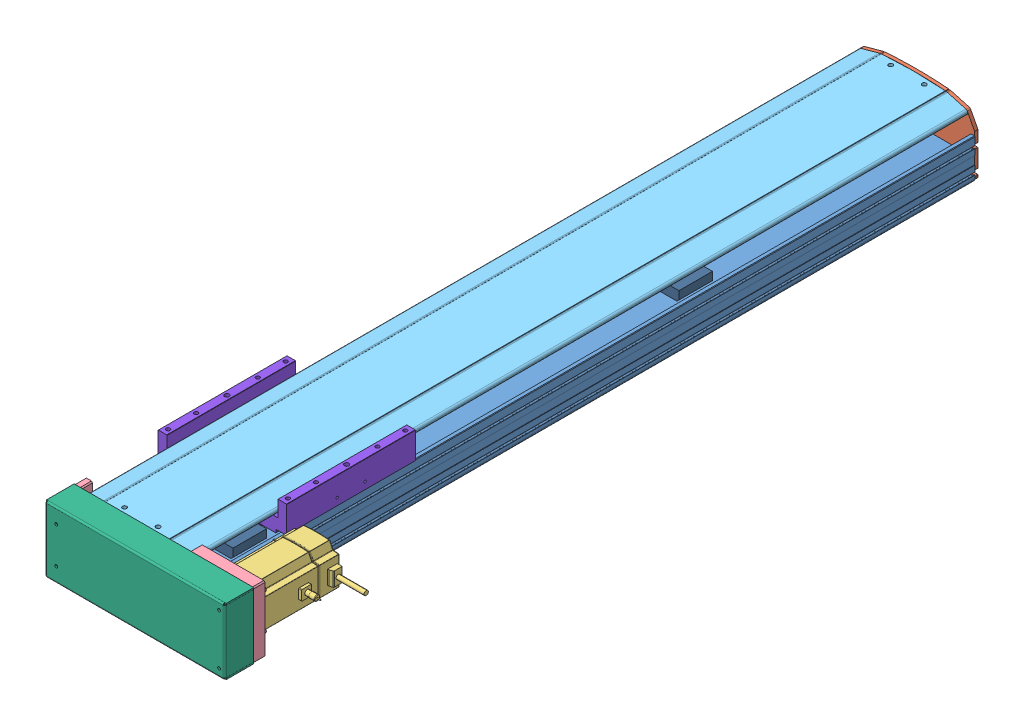
SolidWorks assembly S22M-BL-750W, configuration 默认. Lengths in mm.
Overall size (384.9 122 1448.01).
13 component instances, 10 part files, 39 mates.
Components (placement in the parent):
- S22-BL底座^S22M-BL-750W-1: S22-BL底座^S22M-BL-750W [默认] at origin size (220 71.7 1370) (virtual)
- S22-GY侧盖^S22M-BL-750W-1: S22-GY侧盖^S22M-BL-750W [默认] at (0 0 -691) size (219 117 6) (virtual)
- 750W电机^S22M-BL-750W-1: 750W电机^S22M-BL-750W [默认] at (162.7 60.3 543) x (0 1 0) z (0 0 1) size (82 139.7 182) (virtual)
- S22-BL-P75电机板^S22M-BL-750W-1: S22-BL-P75电机板^S22M-BL-750W [默认] at (0 -0.2 685) size (321 118 20) (virtual)
- S22-BL上盖^S22M-BL-750W-1: S22-BL上盖^S22M-BL-750W [默认] at (0 117.9988 10) size (193.4 19.6 1390) (virtual)
- S22-BL盖子^S22M-BL-750W-1: S22-BL盖子^S22M-BL-750W [默认] at (50.5 59.8 757) size (321.02 118 52.01) (virtual)
- EE-SX672 传感器^S22M-BL-750W-1: EE-SX672 传感器^S22M-BL-750W [默认] at (-116.75 60.4 -424.15) x (-1 0 0) z (0 0 1) size (13.5 27.4 26.1) (virtual)
- EE-SX672 传感器^S22M-BL-750W-2: EE-SX672 传感器^S22M-BL-750W [默认] at (-116.75 60.4 444.9) x (-1 0 0) z (0 0 1) size (13.5 27.4 26.1) (virtual)
- EE-SX672 传感器^S22M-BL-750W-3: EE-SX672 传感器^S22M-BL-750W [默认] at (-116.75 60.4 418.8) x (-1 0 0) z (0 0 1) size (13.5 27.4 26.1) (virtual)
- S22-BL-SFS25滑座^S22M-BL-750W-1: S22-BL-SFS25滑座^S22M-BL-750W [默认] at (0 0.3 435) size (230 80 230) (virtual)
- 复件 外置感应片ST22^S22M-BL-750W-1: 复件 外置感应片ST22^S22M-BL-750W [Default] at (-115 64.3 435) x (0 0 -1) z (1 0 0) size (70 28 1) (virtual)
- 滑座S22M^S22M-BL-750W-1: 滑座S22M^S22M-BL-750W [Default] at (0 60.3 570) size (198 57 60) (virtual)
- 滑座S22M^S22M-BL-750W-2: 滑座S22M^S22M-BL-750W [Default] at (0 60.3 -227) size (198 57 60) (virtual)
Mates (geometry in assembly coordinates):
- 重合1: coincident: plane of S22-BL底座^S22M-BL-750W-1 through (0 0 0) normal (1 0 0); plane of assembly through (0 0 0) normal (1 0 0)
- 重合2: coincident: plane of S22-BL底座^S22M-BL-750W-1 through (0 0 0) normal (0 1 0); plane of assembly through (0 0 0) normal (0 1 0)
- 重合3: coincident: plane of S22-BL底座^S22M-BL-750W-1 through (0 0 0) normal (0 0 1); plane of assembly through (0 0 0) normal (0 0 1)
- 重合4: coincident: plane of S22-BL底座^S22M-BL-750W-1 through (-104.5 14 -685) normal (0 0 -1); plane of S22-GY侧盖^S22M-BL-750W-1 through (0 -619.785 -685) normal (0 0 1)
- 重合5: coincident: plane of S22-BL底座^S22M-BL-750W-1 through (0 0 0) normal (1 0 0); plane of S22-GY侧盖^S22M-BL-750W-1 through (0 0 -691) normal (1 0 0)
- 重合6: coincident: plane of S22-BL底座^S22M-BL-750W-1 through (0 0 0) normal (0 1 0); plane of S22-GY侧盖^S22M-BL-750W-1 through (0 0 -691) normal (0 1 0)
- 距离2: distance = 0.2 mm: plane of S22-BL底座^S22M-BL-750W-1 through (0 0 0) normal (0 1 0); plane of S22-BL-P75电机板^S22M-BL-750W-1 through (0 -0.2 685) normal (0 1 0)
- 重合29: coincident: plane of S22-BL底座^S22M-BL-750W-1 through (0 0 0) normal (1 0 0); plane of S22-BL-P75电机板^S22M-BL-750W-1 through (0 -0.2 685) normal (1 0 0)
- 重合30: coincident: plane of S22-BL底座^S22M-BL-750W-1 through (-104.5 14 685) normal (0 0 1); plane of S22-BL-P75电机板^S22M-BL-750W-1 through (0 -0.2 685) normal (0 0 -1)
- 重合36: coincident: plane of S22-BL底座^S22M-BL-750W-1 through (0 0 0) normal (1 0 0); plane of S22-BL上盖^S22M-BL-750W-1 through (0 117.9988 10) normal (1 0 0)
- 重合130: coincident: plane of S22-BL-P75电机板^S22M-BL-750W-1 through (211 118.8 705) normal (0 1 0); plane of S22-BL盖子^S22M-BL-750W-1 through (208.2 118.8 754.2) normal (0 1 0)
- 重合131: coincident: plane of S22-BL-P75电机板^S22M-BL-750W-1 through (-110 18.3 705) normal (-1 0 0); plane of S22-BL盖子^S22M-BL-750W-1 through (-110 115.9 754.2) normal (-1 0 0)
- 重合132: coincident: plane of S22-BL-P75电机板^S22M-BL-750W-1 through (0 -0.2 705) normal (0 0 1); plane of S22-BL盖子^S22M-BL-750W-1 through (208.2 118.8 705) normal (0 0 -1)
- 重合151: coincident: plane of S22-BL-P75电机板^S22M-BL-750W-1 through (0 -0.2 705) normal (0 0 1); plane of S22-BL上盖^S22M-BL-750W-1 through (59.5897 110.29 705) normal (0 0 1)
- Distance1: distance = 8.3 mm: plane of 750W电机^S22M-BL-750W-1 through (202.7 93.3 677) normal (1 0 0); plane of S22-BL-P75电机板^S22M-BL-750W-1 through (211 0.8 705) normal (1 0 0)
- Distance2: distance = 18.5 mm: plane of 750W电机^S22M-BL-750W-1 through (129.7 100.3 677) normal (0 1 0); plane of S22-BL-P75电机板^S22M-BL-750W-1 through (211 118.8 705) normal (0 1 0)
- Coincident3: coincident: plane of 750W电机^S22M-BL-750W-1 through (162.7 60.3 685) normal (0 0 1); plane of S22-BL-P75电机板^S22M-BL-750W-1 through (0 -0.2 685) normal (0 0 -1)
- Distance3: distance = 122 mm: plane of S22-BL-SFS25滑座^S22M-BL-750W-1 through (99 122.3 550) normal (0 1 0); plane of S22-BL底座^S22M-BL-750W-1 through (110 0.3 685) normal (0 -1 0)
- Coincident5: coincident: plane of S22-BL底座^S22M-BL-750W-1 through (0 0 0) normal (1 0 0); plane of S22-BL-SFS25滑座^S22M-BL-750W-1 through (0 0.3 435) normal (1 0 0)
- Distance4: distance = 117.9988 mm: plane of S22-BL上盖^S22M-BL-750W-1 through (0 117.9988 10) normal (0 1 0); plane of S22-BL底座^S22M-BL-750W-1 through (0 0 0) normal (0 1 0)
- Coincident6: coincident: plane of EE-SX672 传感器^S22M-BL-750W-2 through (-110 71.5 451.2) normal (1 0 0); plane of EE-SX672 传感器^S22M-BL-750W-3 through (-110 71.5 425.1) normal (1 0 0)
- Coincident7: coincident: plane of EE-SX672 传感器^S22M-BL-750W-1 through (-110 71.5 -417.85) normal (1 0 0); plane of EE-SX672 传感器^S22M-BL-750W-2 through (-110 71.5 451.2) normal (1 0 0)
- Coincident8: coincident: plane of EE-SX672 传感器^S22M-BL-750W-2 through (-110 49.3 451.2) normal (0 -1 0); plane of EE-SX672 传感器^S22M-BL-750W-3 through (-110 49.3 425.1) normal (0 -1 0)
- Coincident9: coincident: plane of EE-SX672 传感器^S22M-BL-750W-1 through (-110 49.3 -417.85) normal (0 -1 0); plane of EE-SX672 传感器^S22M-BL-750W-2 through (-110 49.3 451.2) normal (0 -1 0)
- Coincident10: coincident: plane of EE-SX672 传感器^S22M-BL-750W-2 through (-113 52.5 435) normal (0 0 -1); plane of EE-SX672 传感器^S22M-BL-750W-3 through (-113 52.5 435) normal (0 0 1)
- Coincident11: coincident: plane of S22-BL底座^S22M-BL-750W-1 through (-110 42 685) normal (-1 0 0); plane of EE-SX672 传感器^S22M-BL-750W-2 through (-110 71.5 451.2) normal (1 0 0)
- Distance5: distance = 49 mm: plane of EE-SX672 传感器^S22M-BL-750W-1 through (-110 49.3 -417.85) normal (0 -1 0); plane of S22-BL底座^S22M-BL-750W-1 through (-110 0.3 685) normal (0 -1 0)
- Distance7: distance = 260.85 mm: plane of EE-SX672 传感器^S22M-BL-750W-1 through (-123.5 49.3 -424.15) normal (0 0 -1); plane of S22-BL底座^S22M-BL-750W-1 through (-104.5 14 -685) normal (0 0 -1)
- 重合152: coincident: plane of S22-BL-SFS25滑座^S22M-BL-750W-1 through (-115 122.3 550) normal (-1 0 0); plane of 复件 外置感应片ST22^S22M-BL-750W-1 through (-115 64.3 435) normal (1 0 0)
- 同心1: concentric: cylinder of S22-BL-SFS25滑座^S22M-BL-750W-1 through (-115 87.3 410) axis (-1 0 0) radius 2.1; cylinder of 复件 外置感应片ST22^S22M-BL-750W-1 through (-116 87.3 410) axis (1 0 0) radius 2.55
- 同心2: concentric: cylinder of S22-BL-SFS25滑座^S22M-BL-750W-1 through (-115 87.3 460) axis (-1 0 0) radius 2.1; cylinder of 复件 外置感应片ST22^S22M-BL-750W-1 through (-116 87.3 460) axis (1 0 0) radius 2.55
- 重合153: coincident: plane of 滑座S22M^S22M-BL-750W-1 through (-40.6202 86.3 630) normal (0 1 0); plane of 滑座S22M^S22M-BL-750W-2 through (-40.6202 86.3 -167) normal (0 1 0)
- 重合154: coincident: plane of 滑座S22M^S22M-BL-750W-1 through (-99 29.3 570) normal (-1 0 0); plane of 滑座S22M^S22M-BL-750W-2 through (-99 29.3 -227) normal (-1 0 0)
- 重合155: coincident: plane of 滑座S22M^S22M-BL-750W-2 through (0 60.3 -227) normal (1 0 0); plane of assembly through (0 0 0) normal (1 0 0)
- 距离3: distance = 86 mm: plane of 滑座S22M^S22M-BL-750W-1 through (-40.6202 86.3 630) normal (0 1 0); plane of S22-BL底座^S22M-BL-750W-1 through (-110 0.3 685) normal (0 -1 0)
- 距离4: distance: plane of 滑座S22M^S22M-BL-750W-1 through (40.6202 91.3 570) normal (0 0 -1); plane of 滑座S22M^S22M-BL-750W-2 through (40.6202 91.3 -167) normal (0 0 1)
- 距离5: distance = 20 mm: plane of S22-BL-SFS25滑座^S22M-BL-750W-1 through (0 60.3 550) normal (0 0 1); plane of 滑座S22M^S22M-BL-750W-1 through (40.6202 91.3 570) normal (0 0 -1)
- LimitDistance1: limit distance = 6 mm: line of EE-SX672 传感器^S22M-BL-750W-3 through (-113 57.6 435) axis (0 -1 0); plane of 复件 外置感应片ST22^S22M-BL-750W-1 through (-116 64.3 429) normal (0 0 -1)
- 距离7: distance = 322 mm: line of EE-SX672 传感器^S22M-BL-750W-3 through (-113 57.6 435) axis (0 -1 0); plane of S22-BL盖子^S22M-BL-750W-1 through (208.2 118.8 757) normal (0 0 1)
